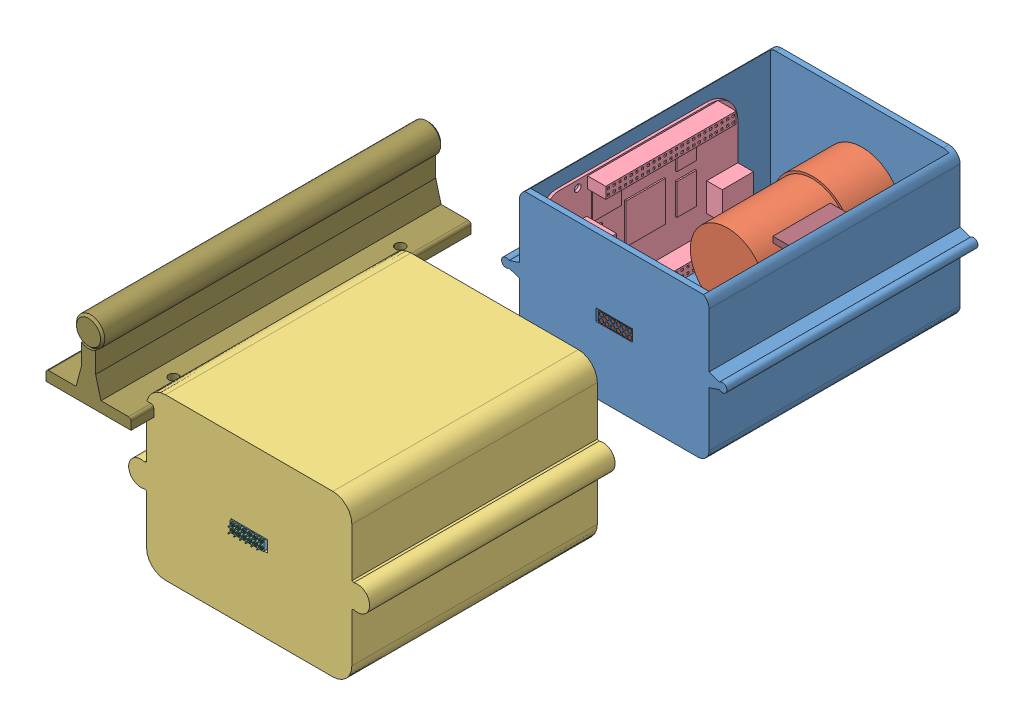
SolidWorks assembly Slide_Rail_Assembly, configuration Default. Lengths in mm.
Overall size (134.85 95.55 297.26).
71 component instances, 14 part files, 11 mates.
Components (placement in the parent):
- Slide_Rail_Reference-1: Slide_Rail_Reference [Default] at origin size (102 66 0)
- Slide_Rail_Motor_Housing-1: Slide_Rail_Motor_Housing [Default] at origin size (102 66 112.5)
- DC_Motor-1: DC_Motor [Default] at (3.1105 -1.5659 4.2169) x (0.443779 0.896074 0.010528) z (-0.896108 0.443828 -0.002752) size (36 75 36)
- Slide_Rail_Outer_Housing-1: Slide_Rail_Outer_Housing [Default] at (0 0 276.0602) x (-1 0 0) z (0 0 -1) size (108 72 110)
- Rough BeagleBone Black-1: Rough BeagleBone Black [Default] at (-40 -28.85 18.3766) x (0 0 -1) z (0 -1 0) size (88.9 14.61 54.61)
- mill-max-818-22-012-10-000101-1: mill-max-818-22-012-10-000101 [Default] at (-7.9444 2.455 273.5602) x (1 0 0) z (0 1 0) size (15.24 8.23 5.08)
  - mill-max-818-22-012-10-000101_P4XX-28-010-00-090000-1: mill-max-818-22-012-10-000101_P4XX-28-010-00-090000 [Default] at origin size (15.24 2.79 5.08)
  - mill-max-818-22-012-10-000101_0963-0-1: mill-max-818-22-012-10-000101_0963-0 [Default] at (0.9644 -4.953 -1.27) x (0 1 0) z (0 0 1) size (4.04 1.31 1.31)
  - mill-max-818-22-012-10-000101_0954-0-1: mill-max-818-22-012-10-000101_0954-0 [Default] at (0.9644 -3.2004 -1.27) x (0 1 0) z (-0.856247 0 0.516567) size (5.03 1.83 1.83)
  - mill-max-818-22-012-10-000101_0918-X-1: mill-max-818-22-012-10-000101_0918-X [Default] at (0.9644 -1.2192 -1.27) x (0 1 0) z (0 0 1) size (4.5 1.25 1.25)
  - mill-max-818-22-012-10-000101_6875-0-00-00-75-XX-43-0C-1: mill-max-818-22-012-10-000101_6875-0-00-00-75-XX-43-0C [Default] at (0.9644 0.6355 -1.27) x (-0.956034 0 -0.293257) z (0 -1 0) size (0.2 0.07 3.45)
  - mill-max-818-22-012-10-000101_0963-0-2: mill-max-818-22-012-10-000101_0963-0 [Default] at (0.9644 -4.953 -3.81) x (0 1 0) z (0 0 1) size (4.04 1.31 1.31)
  - mill-max-818-22-012-10-000101_0954-0-2: mill-max-818-22-012-10-000101_0954-0 [Default] at (0.9644 -3.2004 -3.81) x (0 1 0) z (0.135119 0 0.990829) size (5.03 1.83 1.83)
  - mill-max-818-22-012-10-000101_0918-X-2: mill-max-818-22-012-10-000101_0918-X [Default] at (0.9644 -1.2192 -3.81) x (0 1 0) z (0.012366 0 0.999924) size (4.5 1.25 1.25)
  - mill-max-818-22-012-10-000101_6875-0-00-00-75-XX-43-0C-2: mill-max-818-22-012-10-000101_6875-0-00-00-75-XX-43-0C [Default] at (0.9644 0.6358 -1.27) x (-0.954499 0 -0.298214) z (0 -1 0) size (0.2 0.07 3.45)
  - mill-max-818-22-012-10-000101_6875-0-00-00-75-XX-43-0C-3: mill-max-818-22-012-10-000101_6875-0-00-00-75-XX-43-0C [Default] at (3.5044 0.6358 -1.27) x (-0.954499 0 -0.298214) z (0 -1 0) size (0.2 0.07 3.45)
  - mill-max-818-22-012-10-000101_0918-X-3: mill-max-818-22-012-10-000101_0918-X [Default] at (3.5044 -1.2192 -3.81) x (0 1 0) z (0.012366 0 0.999924) size (4.5 1.25 1.25)
  - mill-max-818-22-012-10-000101_0954-0-3: mill-max-818-22-012-10-000101_0954-0 [Default] at (3.5044 -3.2004 -3.81) x (0 1 0) z (0.135119 0 0.990829) size (5.03 1.83 1.83)
  - mill-max-818-22-012-10-000101_0963-0-3: mill-max-818-22-012-10-000101_0963-0 [Default] at (3.5044 -4.953 -3.81) x (0 1 0) z (0 0 1) size (4.04 1.31 1.31)
  - mill-max-818-22-012-10-000101_6875-0-00-00-75-XX-43-0C-4: mill-max-818-22-012-10-000101_6875-0-00-00-75-XX-43-0C [Default] at (3.5044 0.6355 -1.27) x (-0.956034 0 -0.293257) z (0 -1 0) size (0.2 0.07 3.45)
  - mill-max-818-22-012-10-000101_0918-X-4: mill-max-818-22-012-10-000101_0918-X [Default] at (3.5044 -1.2192 -1.27) x (0 1 0) z (0 0 1) size (4.5 1.25 1.25)
  - mill-max-818-22-012-10-000101_0954-0-4: mill-max-818-22-012-10-000101_0954-0 [Default] at (3.5044 -3.2004 -1.27) x (0 1 0) z (-0.856247 0 0.516567) size (5.03 1.83 1.83)
  - mill-max-818-22-012-10-000101_0963-0-4: mill-max-818-22-012-10-000101_0963-0 [Default] at (3.5044 -4.953 -1.27) x (0 1 0) z (0 0 1) size (4.04 1.31 1.31)
  - mill-max-818-22-012-10-000101_6875-0-00-00-75-XX-43-0C-5: mill-max-818-22-012-10-000101_6875-0-00-00-75-XX-43-0C [Default] at (6.0444 0.6358 -1.27) x (-0.954499 0 -0.298214) z (0 -1 0) size (0.2 0.07 3.45)
  - mill-max-818-22-012-10-000101_6875-0-00-00-75-XX-43-0C-6: mill-max-818-22-012-10-000101_6875-0-00-00-75-XX-43-0C [Default] at (8.5844 0.6358 -1.27) x (-0.954499 0 -0.298214) z (0 -1 0) size (0.2 0.07 3.45)
  - mill-max-818-22-012-10-000101_6875-0-00-00-75-XX-43-0C-7: mill-max-818-22-012-10-000101_6875-0-00-00-75-XX-43-0C [Default] at (11.1244 0.6358 -1.27) x (-0.954499 0 -0.298214) z (0 -1 0) size (0.2 0.07 3.45)
  - mill-max-818-22-012-10-000101_6875-0-00-00-75-XX-43-0C-8: mill-max-818-22-012-10-000101_6875-0-00-00-75-XX-43-0C [Default] at (13.6644 0.6358 -1.27) x (-0.954499 0 -0.298214) z (0 -1 0) size (0.2 0.07 3.45)
  - mill-max-818-22-012-10-000101_0918-X-5: mill-max-818-22-012-10-000101_0918-X [Default] at (6.0444 -1.2192 -3.81) x (0 1 0) z (0.012366 0 0.999924) size (4.5 1.25 1.25)
  - mill-max-818-22-012-10-000101_0918-X-6: mill-max-818-22-012-10-000101_0918-X [Default] at (8.5844 -1.2192 -3.81) x (0 1 0) z (0.012366 0 0.999924) size (4.5 1.25 1.25)
  - mill-max-818-22-012-10-000101_0918-X-7: mill-max-818-22-012-10-000101_0918-X [Default] at (11.1244 -1.2192 -3.81) x (0 1 0) z (0.012366 0 0.999924) size (4.5 1.25 1.25)
  - mill-max-818-22-012-10-000101_0918-X-8: mill-max-818-22-012-10-000101_0918-X [Default] at (13.6644 -1.2192 -3.81) x (0 1 0) z (0.012366 0 0.999924) size (4.5 1.25 1.25)
  - mill-max-818-22-012-10-000101_0954-0-5: mill-max-818-22-012-10-000101_0954-0 [Default] at (6.0444 -3.2004 -3.81) x (0 1 0) z (0.135119 0 0.990829) size (5.03 1.83 1.83)
  - mill-max-818-22-012-10-000101_0954-0-6: mill-max-818-22-012-10-000101_0954-0 [Default] at (8.5844 -3.2004 -3.81) x (0 1 0) z (0.135119 0 0.990829) size (5.03 1.83 1.83)
  - mill-max-818-22-012-10-000101_0954-0-7: mill-max-818-22-012-10-000101_0954-0 [Default] at (11.1244 -3.2004 -3.81) x (0 1 0) z (0.135119 0 0.990829) size (5.03 1.83 1.83)
  - mill-max-818-22-012-10-000101_0954-0-8: mill-max-818-22-012-10-000101_0954-0 [Default] at (13.6644 -3.2004 -3.81) x (0 1 0) z (0.135119 0 0.990829) size (5.03 1.83 1.83)
  - mill-max-818-22-012-10-000101_0963-0-5: mill-max-818-22-012-10-000101_0963-0 [Default] at (6.0444 -4.953 -3.81) x (0 1 0) z (0 0 1) size (4.04 1.31 1.31)
  - mill-max-818-22-012-10-000101_0963-0-6: mill-max-818-22-012-10-000101_0963-0 [Default] at (8.5844 -4.953 -3.81) x (0 1 0) z (0 0 1) size (4.04 1.31 1.31)
  - mill-max-818-22-012-10-000101_0963-0-7: mill-max-818-22-012-10-000101_0963-0 [Default] at (11.1244 -4.953 -3.81) x (0 1 0) z (0 0 1) size (4.04 1.31 1.31)
  - mill-max-818-22-012-10-000101_0963-0-8: mill-max-818-22-012-10-000101_0963-0 [Default] at (13.6644 -4.953 -3.81) x (0 1 0) z (0 0 1) size (4.04 1.31 1.31)
  - mill-max-818-22-012-10-000101_6875-0-00-00-75-XX-43-0C-9: mill-max-818-22-012-10-000101_6875-0-00-00-75-XX-43-0C [Default] at (6.0444 0.6355 -1.27) x (-0.956034 0 -0.293257) z (0 -1 0) size (0.2 0.07 3.45)
  - mill-max-818-22-012-10-000101_6875-0-00-00-75-XX-43-0C-10: mill-max-818-22-012-10-000101_6875-0-00-00-75-XX-43-0C [Default] at (8.5844 0.6355 -1.27) x (-0.956034 0 -0.293257) z (0 -1 0) size (0.2 0.07 3.45)
  - mill-max-818-22-012-10-000101_6875-0-00-00-75-XX-43-0C-11: mill-max-818-22-012-10-000101_6875-0-00-00-75-XX-43-0C [Default] at (11.1244 0.6355 -1.27) x (-0.956034 0 -0.293257) z (0 -1 0) size (0.2 0.07 3.45)
  - mill-max-818-22-012-10-000101_6875-0-00-00-75-XX-43-0C-12: mill-max-818-22-012-10-000101_6875-0-00-00-75-XX-43-0C [Default] at (13.6644 0.6355 -1.27) x (-0.956034 0 -0.293257) z (0 -1 0) size (0.2 0.07 3.45)
  - mill-max-818-22-012-10-000101_0918-X-9: mill-max-818-22-012-10-000101_0918-X [Default] at (6.0444 -1.2192 -1.27) x (0 1 0) z (0 0 1) size (4.5 1.25 1.25)
  - mill-max-818-22-012-10-000101_0918-X-10: mill-max-818-22-012-10-000101_0918-X [Default] at (8.5844 -1.2192 -1.27) x (0 1 0) z (0 0 1) size (4.5 1.25 1.25)
  - mill-max-818-22-012-10-000101_0918-X-11: mill-max-818-22-012-10-000101_0918-X [Default] at (11.1244 -1.2192 -1.27) x (0 1 0) z (0 0 1) size (4.5 1.25 1.25)
  - mill-max-818-22-012-10-000101_0918-X-12: mill-max-818-22-012-10-000101_0918-X [Default] at (13.6644 -1.2192 -1.27) x (0 1 0) z (0 0 1) size (4.5 1.25 1.25)
  - mill-max-818-22-012-10-000101_0954-0-9: mill-max-818-22-012-10-000101_0954-0 [Default] at (6.0444 -3.2004 -1.27) x (0 1 0) z (-0.856247 0 0.516567) size (5.03 1.83 1.83)
  - mill-max-818-22-012-10-000101_0954-0-10: mill-max-818-22-012-10-000101_0954-0 [Default] at (8.5844 -3.2004 -1.27) x (0 1 0) z (-0.856247 0 0.516567) size (5.03 1.83 1.83)
  - mill-max-818-22-012-10-000101_0954-0-11: mill-max-818-22-012-10-000101_0954-0 [Default] at (11.1244 -3.2004 -1.27) x (0 1 0) z (-0.856247 0 0.516567) size (5.03 1.83 1.83)
  - mill-max-818-22-012-10-000101_0954-0-12: mill-max-818-22-012-10-000101_0954-0 [Default] at (13.6644 -3.2004 -1.27) x (0 1 0) z (-0.856247 0 0.516567) size (5.03 1.83 1.83)
  - mill-max-818-22-012-10-000101_0963-0-9: mill-max-818-22-012-10-000101_0963-0 [Default] at (6.0444 -4.953 -1.27) x (0 1 0) z (0 0 1) size (4.04 1.31 1.31)
  - mill-max-818-22-012-10-000101_0963-0-10: mill-max-818-22-012-10-000101_0963-0 [Default] at (8.5844 -4.953 -1.27) x (0 1 0) z (0 0 1) size (4.04 1.31 1.31)
  - mill-max-818-22-012-10-000101_0963-0-11: mill-max-818-22-012-10-000101_0963-0 [Default] at (11.1244 -4.953 -1.27) x (0 1 0) z (0 0 1) size (4.04 1.31 1.31)
  - mill-max-818-22-012-10-000101_0963-0-12: mill-max-818-22-012-10-000101_0963-0 [Default] at (13.6644 -4.953 -1.27) x (0 1 0) z (0 0 1) size (4.04 1.31 1.31)
- mill-max-419-10-212-00-001000-1: mill-max-419-10-212-00-001000 [Default] at (-6.6844 -2.625 112.5) x (1 0 0) z (0 -1 0) size (15.24 7.37 5.08)
  - mill-max-419-10-212-00-001000_P4XX-21-010-00-000000-1: mill-max-419-10-212-00-001000_P4XX-21-010-00-000000 [Default] at origin size (15.24 2.79 5.08)
  - mill-max-419-10-212-00-001000_1942-1: mill-max-419-10-212-00-001000_1942 [Default] at (0.9644 0 -1.27) x (0 -1 0) z (0 0 1) size (7.37 1.78 1.78)
  - mill-max-419-10-212-00-001000_1942-2: mill-max-419-10-212-00-001000_1942 [Default] at (0.9644 0 -3.81) x (0 -1 0) z (0 0 1) size (7.37 1.78 1.78)
  - mill-max-419-10-212-00-001000_1942-3: mill-max-419-10-212-00-001000_1942 [Default] at (3.5044 0 -3.81) x (0 -1 0) z (0 0 1) size (7.37 1.78 1.78)
  - mill-max-419-10-212-00-001000_1942-4: mill-max-419-10-212-00-001000_1942 [Default] at (3.5044 0 -1.27) x (0 -1 0) z (0 0 1) size (7.37 1.78 1.78)
  - mill-max-419-10-212-00-001000_1942-5: mill-max-419-10-212-00-001000_1942 [Default] at (6.0444 0 -3.81) x (0 -1 0) z (0 0 1) size (7.37 1.78 1.78)
  - mill-max-419-10-212-00-001000_1942-6: mill-max-419-10-212-00-001000_1942 [Default] at (8.5844 0 -3.81) x (0 -1 0) z (0 0 1) size (7.37 1.78 1.78)
  - mill-max-419-10-212-00-001000_1942-7: mill-max-419-10-212-00-001000_1942 [Default] at (11.1244 0 -3.81) x (0 -1 0) z (0 0 1) size (7.37 1.78 1.78)
  - mill-max-419-10-212-00-001000_1942-8: mill-max-419-10-212-00-001000_1942 [Default] at (13.6644 0 -3.81) x (0 -1 0) z (0 0 1) size (7.37 1.78 1.78)
  - mill-max-419-10-212-00-001000_1942-9: mill-max-419-10-212-00-001000_1942 [Default] at (6.0444 0 -1.27) x (0 -1 0) z (0 0 1) size (7.37 1.78 1.78)
  - mill-max-419-10-212-00-001000_1942-10: mill-max-419-10-212-00-001000_1942 [Default] at (8.5844 0 -1.27) x (0 -1 0) z (0 0 1) size (7.37 1.78 1.78)
  - mill-max-419-10-212-00-001000_1942-11: mill-max-419-10-212-00-001000_1942 [Default] at (11.1244 0 -1.27) x (0 -1 0) z (0 0 1) size (7.37 1.78 1.78)
  - mill-max-419-10-212-00-001000_1942-12: mill-max-419-10-212-00-001000_1942 [Default] at (13.6644 0 -1.27) x (0 -1 0) z (0 0 1) size (7.37 1.78 1.78)
- Slide_Rail_1049K110-1: Slide_Rail_1049K110 [1049K11] at (-61.7999 24.627 210.0434) size (38.1 34.92 152.4)
- Motor Driver-1: Motor Driver [Default] at (37.5 -1.5453 55.6645) x (0 0 1) z (-1 0 0) size (65.1 51.35 16.5)
Mates (geometry in assembly coordinates):
- Concentric2: concentric anti-aligned: cylinder of Slide_Rail_Motor_Housing-1 through (-48.5 0 110) axis (0 0 -1) radius 2; cylinder of Slide_Rail_Outer_Housing-1 through (-48.5 0 166.0602) axis (0 0 1) radius 2.5
- Concentric3: concentric anti-aligned: cylinder of Slide_Rail_Motor_Housing-1 through (48.5 0 110) axis (0 0 -1) radius 2; cylinder of Slide_Rail_Outer_Housing-1 through (48.5 0 166.0602) axis (0 0 1) radius 2.5
- Coincident8: coincident aligned: plane of Slide_Rail_Outer_Housing-1 through (-37.5 27.5 273.5602) normal (0 0 -1); plane of mill-max-818-22-012-10-000101-1/mill-max-818-22-012-10-000101_P4XX-28-010-00-090000-1 through (-8.25 -2.625 273.5602) normal (0 0 -1)
- Coincident9: coincident anti-aligned: plane of Slide_Rail_Outer_Housing-1 through (-8.25 -2.625 273.5602) normal (1 0 0); plane of mill-max-818-22-012-10-000101-1/mill-max-818-22-012-10-000101_P4XX-28-010-00-090000-1 through (-8.25 -2.2249 276.3542) normal (-1 0 0)
- Coincident10: coincident anti-aligned: plane of Slide_Rail_Outer_Housing-1 through (8.25 -2.625 273.5602) normal (0 1 0); plane of mill-max-818-22-012-10-000101-1/mill-max-818-22-012-10-000101_P4XX-28-010-00-090000-1 through (6.6844 -2.625 276.3542) normal (0 -1 0)
- Coincident11: coincident anti-aligned: plane of Slide_Rail_Motor_Housing-1 through (-8.25 -2.625 112.5) normal (0 1 0); plane of mill-max-419-10-212-00-001000-1/mill-max-419-10-212-00-001000_P4XX-21-010-00-000000-1 through (-1.6044 -2.625 109.706) normal (0 -1 0)
- Coincident12: coincident anti-aligned: plane of Slide_Rail_Motor_Housing-1 through (8.25 -2.625 112.5) normal (-1 0 0); plane of mill-max-419-10-212-00-001000-1/mill-max-419-10-212-00-001000_P4XX-21-010-00-000000-1 through (8.25 -2.2249 109.706) normal (1 0 0)
- Coincident13: coincident aligned: plane of Slide_Rail_Motor_Housing-1 through (-48.5 0 112.5) normal (0 0 1); plane of mill-max-419-10-212-00-001000-1/mill-max-419-10-212-00-001000_P4XX-21-010-00-000000-1 through (-6.99 2.455 112.5) normal (0 0 1)
- Coincident14: coincident anti-aligned: plane of Slide_Rail_Motor_Housing-1 through (40 -28.0882 110) normal (-1 0 0); plane of Motor Driver-1 through (40 -1.5453 55.6645) normal (1 0 0)
- Concentric5: concentric: cylinder of Slide_Rail_Motor_Housing-1 through (-50.501 -25.675 90.1316) axis (1 0 0) radius 1.524; cylinder of Rough BeagleBone Black-1 through (-44.3105 -25.675 90.1316) axis (1 0 0) radius 1.524
- Concentric6: concentric aligned: cylinder of Slide_Rail_Motor_Housing-1 through (-50.501 -22.5 24.0916) axis (1 0 0) radius 1.524; cylinder of Rough BeagleBone Black-1 through (-44.3105 -22.5 24.0916) axis (1 0 0) radius 1.524
